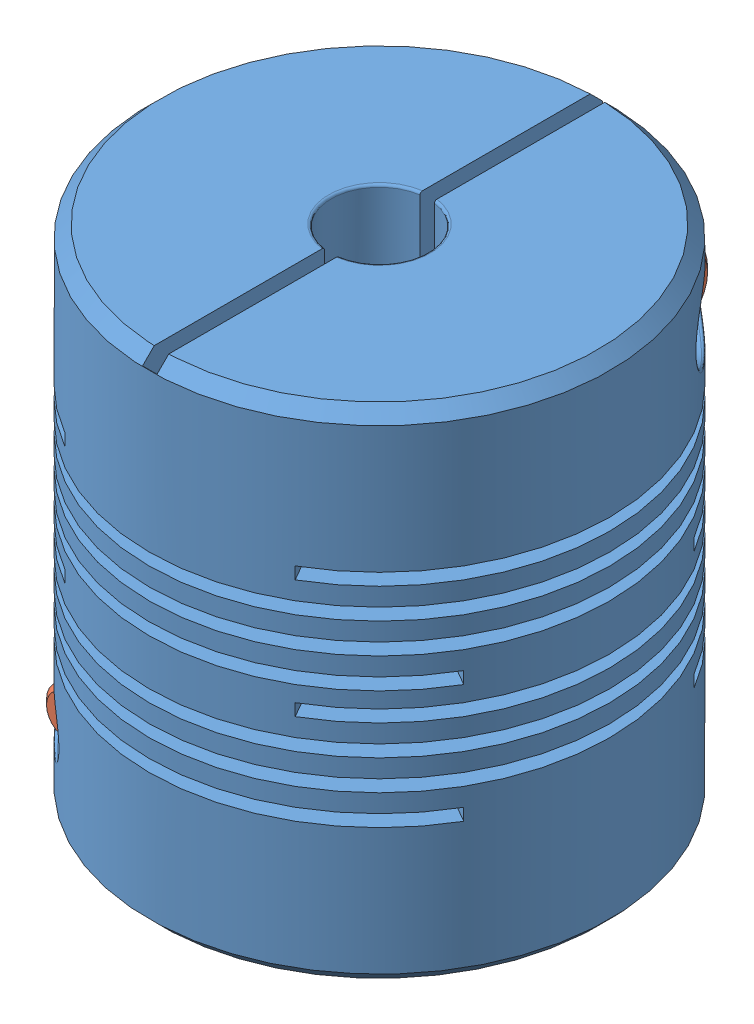
SolidWorks assembly MKS-C-2-C-150-08-10, configuration Default. Lengths in mm.
Overall size (38.1 41.32 38.1).
3 component instances, 2 part files, 4 mates.
Components (placement in the parent):
- MKS-C-2-C-150-08-10-1-1: MKS-C-2-C-150-08-10-1 [Default] at (-7.3634 16.4351 -7.2802) size (38.1 41.32 38.1)
- socket head cap screw_am-3: socket head cap screw_am [B18.3.1M - 4 x 0.7 x 20 Hex SHCS -- 20NHX] at (3.6866 10.4351 -20.2802) x (-1 0 0) z (0 0.924225 0.381849) size (24 7 7)
- socket head cap screw_am-4: socket head cap screw_am [B18.3.1M - 4 x 0.7 x 20 Hex SHCS -- 20NHX] at (-20.3634 -18.8649 -18.3302) x (0 0 1) z (-1 0 0) size (24 7 7)
Mates (geometry in assembly coordinates):
- Concentric1: concentric aligned: cylinder of MKS-C-2-C-150-08-10-1-1 through (-0.3134 10.4351 -20.2802) axis (1 0 0) radius 3; cylinder of socket head cap screw_am-3 through (35.4366 10.4351 -20.2802) axis (1 0 0) radius 2
- Coincident1: coincident anti-aligned: plane of MKS-C-2-C-150-08-10-1-1 through (-0.3134 10.4351 -20.2802) normal (1 0 0); plane of socket head cap screw_am-3 through (-0.3134 9.0987 -17.0454) normal (-1 0 0)
- Concentric2: concentric anti-aligned: cylinder of MKS-C-2-C-150-08-10-1-1 through (-20.3634 -18.8649 -26.3312) axis (0 0 1) radius 2; cylinder of socket head cap screw_am-4 through (-20.3634 -18.8649 -50.0802) axis (0 0 -1) radius 3.5
- Coincident2: coincident anti-aligned: plane of MKS-C-2-C-150-08-10-1-1 through (-20.3634 -18.8649 -14.3302) normal (0 0 -1); plane of socket head cap screw_am-4 through (-20.3634 -15.3649 -14.3302) normal (0 0 1)
